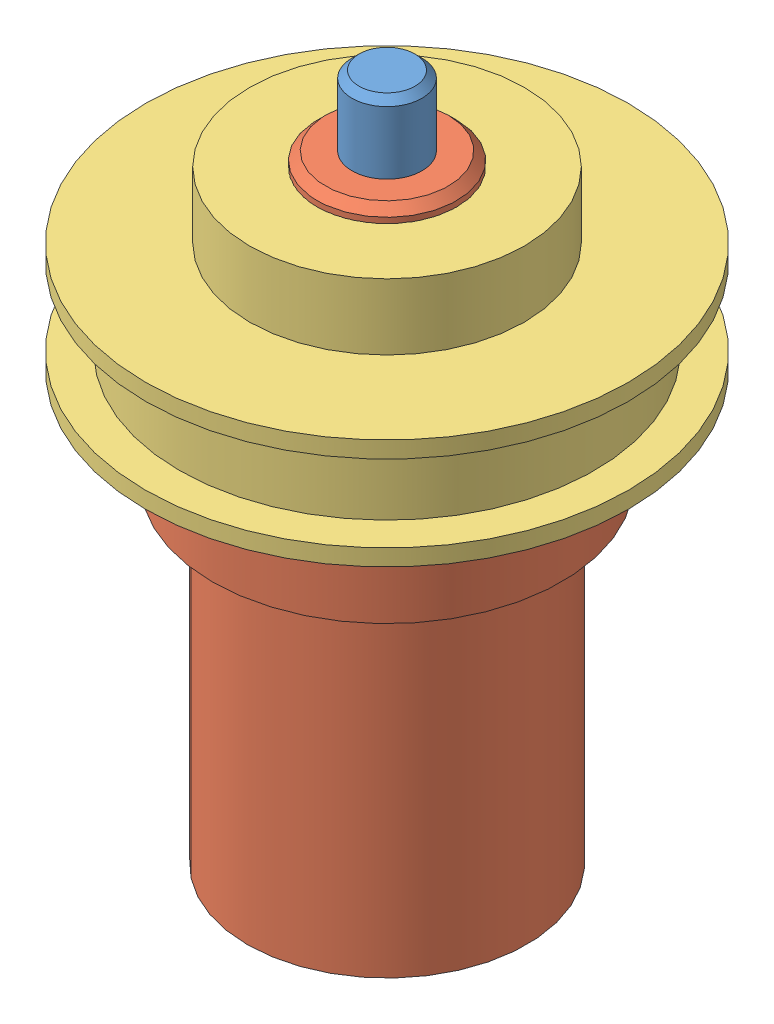
SolidWorks assembly TimingBeltDriveShaftAssembly, configuration Default. Lengths in mm.
Overall size (43.94 62.55 43.94).
6 component instances, 5 part files, 13 mates.
Components (placement in the parent):
- MazdaMotorWinchShaftTimingBelt-1: MazdaMotorWinchShaftTimingBelt [Default] at origin (suppressed, hidden)
- 60-GT2 8mm bore 6mm belt-1: 60-GT2 8mm bore 6mm belt [Default] at (22.7129 46.8175 -12.9452) x (-0.837169 0 -0.546944) z (0 1 0) (suppressed, hidden)
- 90145A537_18-8 STAINLESS STEEL DOWEL PIN-1: 90145A537_18-8 STAINLESS STEEL DOWEL PIN [90145A537] at (0 56.1975 0) x (0 -1 0) z (-0.922963 0 0.384889) size (12.7 6.35 6.35)
- 5  MazdaMotorWinchShaft-1: 5  MazdaMotorWinchShaft [Adjustment] at origin size (31.75 56.2 31.75)
- 60-GT2 8mm bore 6mm belt-2: 60-GT2 8mm bore 6mm belt [ForRemachinedShaft] at (11.9343 47.4382 23.2601) x (-1 0 0) z (0 -1 0) size (44 44 16.9) (hidden)
- 60tGT2Pulley-1: 60tGT2Pulley [Default] at (0 38.9382 0) x (-1 0 0) z (0 0 -1) size (43.94 16 43.94)
Mates (geometry in assembly coordinates):
- Concentric1: concentric: cylinder of MazdaMotorWinchShaftTimingBelt-1 through (0 56.1975 0) axis (0 -1 0) radius 9.525; cylinder of 60tGT2Pulley-1 through (0 38.4175 0) axis (0 1 0) radius 9.525
- Coincident1: coincident anti-aligned: plane of MazdaMotorWinchShaftTimingBelt-1 through (0 38.4175 0) normal (0 1 0); plane of 60tGT2Pulley-1 through (-21.8093 38.4175 -2.6609) normal (0 -1 0)
- Concentric2: concentric anti-aligned: cylinder of MazdaMotorWinchShaftTimingBelt-1 through (0 49.8475 0) axis (0 1 0) radius 3.1496; cylinder of 90145A537_18-8 STAINLESS STEEL DOWEL PIN-1 through (0 62.5475 0) axis (0 -1 0) radius 3.175
- Coincident3: coincident anti-aligned: plane of MazdaMotorWinchShaftTimingBelt-1 through (0 49.8475 0) normal (0 1 0); plane of 90145A537_18-8 STAINLESS STEEL DOWEL PIN-1 through (0 49.8475 0) normal (0 -1 0)
- Concentric3: concentric aligned: cylinder of MazdaMotorWinchShaftTimingBelt-1 through (0 56.1975 0) axis (0 -1 0) radius 9.525; cylinder of 60-GT2 8mm bore 6mm belt-1 through (0 91.2385 0) axis (0 -1 0) radius 12.7
- Coincident4: coincident anti-aligned: plane of MazdaMotorWinchShaftTimingBelt-1 through (0 38.4175 0) normal (0 1 0); plane of 60-GT2 8mm bore 6mm belt-1 through (0 38.4175 0) normal (0 -1 0)
- Coincident6: coordinate: point of ?
- Concentric4: concentric anti-aligned: cylinder of 90145A537_18-8 STAINLESS STEEL DOWEL PIN-1 through (0 62.5475 0) axis (0 -1 0) radius 3.175; cylinder of 5  MazdaMotorWinchShaft-1 through (0 87.5665 0) axis (0 1 0) radius 6.3627
- Coincident7: coincident anti-aligned: plane of 90145A537_18-8 STAINLESS STEEL DOWEL PIN-1 through (0 49.8475 0) normal (0 -1 0); circle of 5  MazdaMotorWinchShaft-1
- Concentric5: concentric anti-aligned: cylinder of 5  MazdaMotorWinchShaft-1 through (0 87.5665 0) axis (0 1 0) radius 6.3627; cylinder of 60-GT2 8mm bore 6mm belt-2 through (0 55.9382 0) axis (0 -1 0) radius 6.35
- Coincident8: coincident anti-aligned: plane of 5  MazdaMotorWinchShaft-1 through (0 38.9382 0) normal (0 1 0); plane of 60-GT2 8mm bore 6mm belt-2 through (0 38.9382 0) normal (0 -1 0)
- Coincident9: coincident anti-aligned: plane of 5  MazdaMotorWinchShaft-1 through (0 38.9382 0) normal (0 1 0); plane of 60tGT2Pulley-1 through (21.971 38.9382 0) normal (0 -1 0)
- Concentric7: concentric aligned: cylinder of 5  MazdaMotorWinchShaft-1 through (0 87.5665 0) axis (0 1 0) radius 6.3627; cylinder of 60tGT2Pulley-1 through (0 54.9382 0) axis (0 -1 0) radius 6.35
